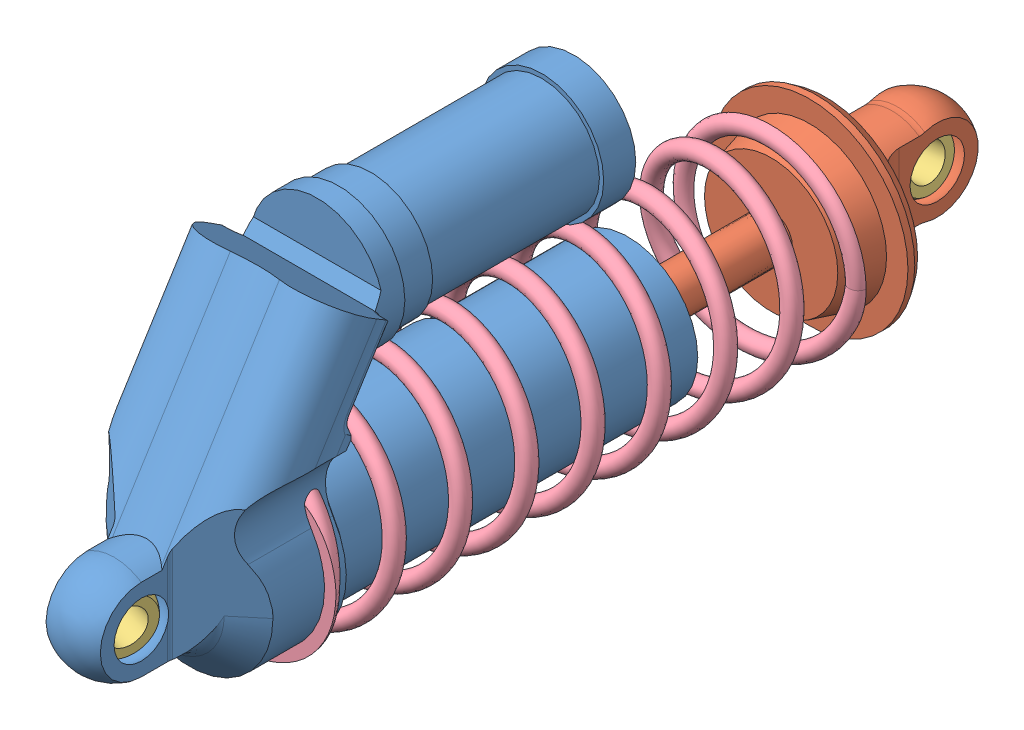
SolidWorks assembly SP-A0105-AC-Ohlin TTX25 MKII, 200mm, configuration Static. Lengths in mm.
Overall size (48.39 85.02 209.16).
5 component instances, 4 part files, 15 mates.
Components (placement in the parent):
- Shock Body^SP-A0105-AC-Ohlin TTX25 MKII, 200mm-1: Shock Body^SP-A0105-AC-Ohlin TTX25 MKII, 200mm [Default] at origin size (40.76 80 131.7) (virtual)
- Head^SP-A0105-AC-Ohlin TTX25 MKII, 200mm-1: Head^SP-A0105-AC-Ohlin TTX25 MKII, 200mm [Default] at (0 0 -186.1566) size (46 46 119) (virtual)
- Ball^SP-A0105-AC-Ohlin TTX25 MKII, 200mm-1: Ball^SP-A0105-AC-Ohlin TTX25 MKII, 200mm [Default] at (0 0 -186.1566) x (-0.011681 0.107343 0.994153) z (0.993776 0.111394 -0.000351) size (15 15 8) (virtual)
- Ball^SP-A0105-AC-Ohlin TTX25 MKII, 200mm-2: Ball^SP-A0105-AC-Ohlin TTX25 MKII, 200mm [Default] x (0.079523 -0.862756 -0.499328) z (0.965926 -0.057074 0.252448) size (15 15 8) (virtual)
- SP-#####-AB-Spring-1: SP-#####-AB-Spring [Default] at (0 0 -153.7171) size (48.39 49.05 127.97)
Mates (geometry in assembly coordinates):
- Coincident1: coordinate: point of Copy of Shock Body^Assem1-1
- Coincident2: coincident aligned: plane of Head^SP-A0105-AC-Ohlin TTX25 MKII, 200mm-1 through (0 0 -186.1566) normal (1 0 0)
- Coincident3: coincident aligned: plane of Head^SP-A0105-AC-Ohlin TTX25 MKII, 200mm-1 through (0 0 -186.1566) normal (0 1 0)
- Distance1: distance = 186.1566 mm aligned: plane of Head^SP-A0105-AC-Ohlin TTX25 MKII, 200mm-1 through (0 0 -186.1566) normal (0 0 1); plane of Shock Body^SP-A0105-AC-Ohlin TTX25 MKII, 200mm-1 through (0 0 0) normal (0 0 1)
- Distance2: distance = 209.55 mm aligned: plane of Shock Body^SP-A0105-AC-Ohlin TTX25 MKII, 200mm-1 through (0 0 0) normal (0 0 1); plane of Head^SP-A0105-AC-Ohlin TTX25 MKII, 200mm-1 through (0 0 -186.1566) normal (0 0 1)
- Distance3: distance = 152.4 mm: plane of Head^SP-A0105-AC-Ohlin TTX25 MKII, 200mm-1 through (0 0 -192.024) normal (0 0 1); plane of Shock Body^SP-A0105-AC-Ohlin TTX25 MKII, 200mm-1 through (0 0 0) normal (0 0 1)
- Coincident7: coincident: point of Shock Body^SP-A0105-AB-Ohlin TTX25 MKII, 200mm-1; point of Ball^SP-A0105-AC-Ohlin TTX25 MKII, 200mm-2
- LimitAngle1: limit planar angle = 0.111627 rad aligned: plane of assembly through (0 0 0) normal (1 0 0); plane of ? through (0 0 -174.6) normal (0.993776 0.111394 -0.000351)
- LimitAngle2: limit planar angle = 0.261799 rad aligned: plane of Ball^SP-A0105-AC-Ohlin TTX25 MKII, 200mm-2 through (0 0 0) normal (0.965926 -0.057074 0.252448)
- Parallel1: parallel aligned: plane of Head^SP-A0105-AC-Ohlin TTX25 MKII, 200mm-1 through (0 0 -162.6566) normal (0 0 1); plane of SP-#####-AB-Spring-1 through (0 0 -153.7171) normal (0 0 1)
- Concentric1: concentric anti-aligned: cylinder of Head^SP-A0105-AC-Ohlin TTX25 MKII, 200mm-1 through (0 0 -78.6566) axis (0 0 -1) radius 5; circle of Spring-1
- Concentric2: concentric anti-aligned: cylinder of Shock Body^SP-0####-XC-Ohlin TTX25 MKII, 200mm-1 through (0 0 974.6008) axis (0 0 1) radius 16.3; cylinder of Head^SP-A0105-AC-Ohlin TTX25 MKII, 200mm-1 through (0 0 -77.157) axis (0 0 -1) radius 5
- Angle1: planar angle = 2.792527 rad aligned: plane of Head^SP-A0105-AC-Ohlin TTX25 MKII, 200mm-1 through (0 0 -177.6) normal (1 0 0)
- Angle2: planar angle = 0.349066 rad aligned: plane of Head^SP-A0105-AC-Ohlin TTX25 MKII, 200mm-1 through (0 0 -177.6) normal (1 0 0)
- Concentric3: concentric: sphere of Head^SP-A0105-AC-Ohlin TTX25 MKII, 200mm-1; sphere of Ball^SP-A0105-AC-Ohlin TTX25 MKII, 200mm-1
